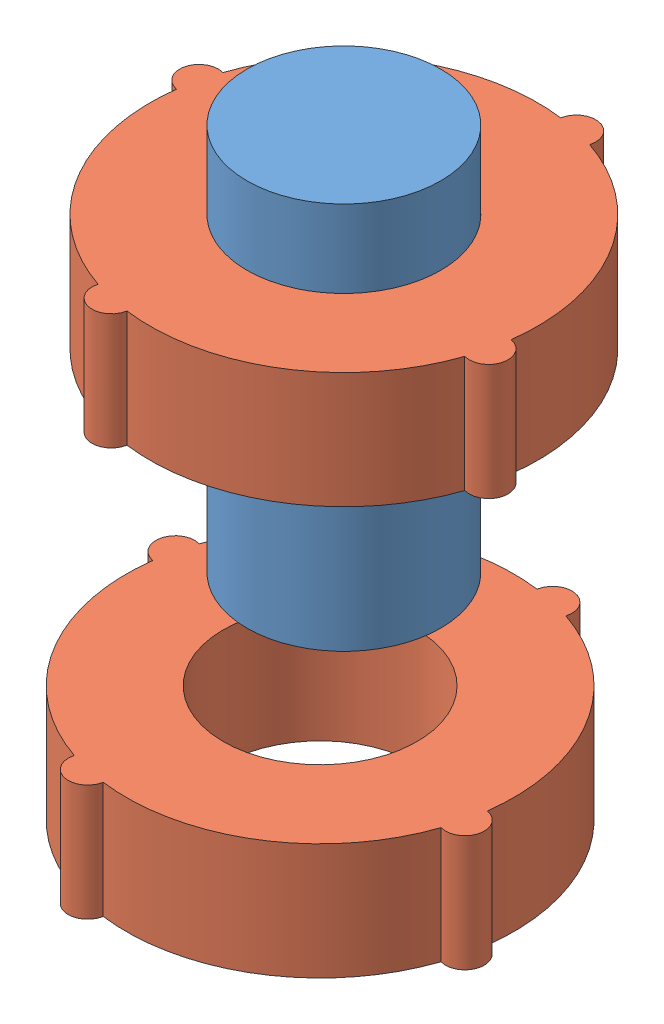
SolidWorks assembly Ensamblaje3, configuration Predeterminado. Lengths in mm.
Overall size (151.85 132.48 157.98).
3 component instances, 2 part files, 2 mates.
Components (placement in the parent):
- Pieza1-1: Pieza1 [Predeterminado] at (63.8277 29.1829 80.1898) size (50 100 50)
- Pieza2-1: Pieza2 [Predeterminado] at (63.8277 79.1829 80.1898) x (0.226383 0 -0.974038) z (0.974038 0 0.226383) size (110 30 110)
- Pieza2-2: Pieza2 [Predeterminado] at (83.634 -3.3005 106.1276) x (0.226383 0 -0.974038) z (0.974038 0 0.226383) size (110 30 110)
Mates (geometry in assembly coordinates):
- Concéntrica1: concentric: cylinder of Pieza1-1 through (63.8277 129.1829 80.1898) axis (0 -1 0) radius 25; cylinder of ? through (63.8411 56.553 80.1903) axis (-0.000178 -1 0.000674) radius 25
- Distancia1: distance = 20 mm: plane of assembly; plane of assembly; plane of Pieza1-1 through (63.8277 129.1829 80.1898) normal (0 1 0); plane of Pieza2-1 through (88.1787 109.1829 85.8494) normal (0 1 0)
